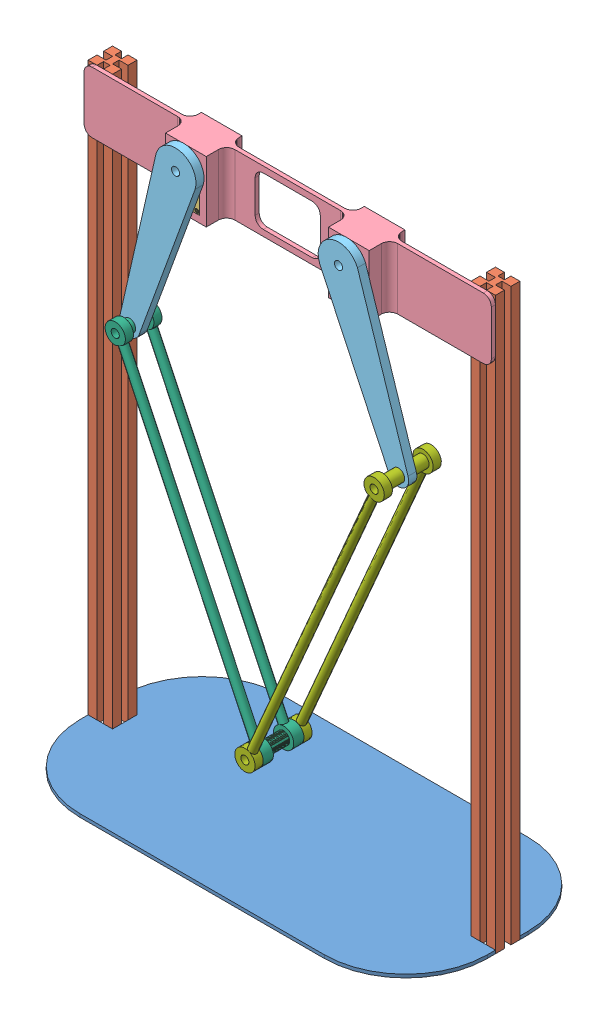
SolidWorks assembly 2dof, configuration Default. Lengths in mm.
Overall size (500 710.46 250).
10 component instances, 7 part files, 24 mates.
Components (placement in the parent):
- base_plate-1: base_plate [Default] at (211.4596 209.3847 404.3525) size (500 4 250)
- strud50-1: strud50 [Default] at (-27.5404 209.3847 411.3525) size (30 700 30)
- strud50-2: strud50 [Default] at (442.4596 209.3847 411.3525) size (30 700 30)
- DynamyxelXM150-1: DynamyxelXM150 [Default] at (111.4889 871.8847 405.3525) x (0 -1 0) z (-1 0 0) size (58.5 49.15 33.5)
- stand-1: stand [Default] at (211.4596 871.8847 419.3525) size (500 75 44)
- DynamyxelXM150-3: DynamyxelXM150 [Default] at (311.4596 871.8864 405.3525) x (0 -1 0) z (-1 0 0) size (58.5 49.15 33.5)
- up_link-1: up_link [Default] at (348.3193 794.4275 452.0025) x (0.929589 0.368597 0) z (0 0 1) size (50 237.5 10)
- up_link-2: up_link [Default] at (83.2023 791.4688 452.0025) x (0.959159 -0.282866 0) z (0 0 1) size (50 237.5 10)
- down_link2-1: down_link2 [Default] at (54.9157 695.5528 434.5025) x (0.903238 0.429141 0) z (0 0 1) size (25 425 50)
- down_link-2: down_link [Default] at (385.179 701.4686 422.0025) x (0.918027 -0.396518 0) z (0 0 1) size (25 425 70)
Mates (geometry in assembly coordinates):
- Coincident2: coincident aligned: plane of base_plate-1 through (-38.5404 213.3847 529.3525) normal (-1 0 0); plane of strud50-1 through (-38.5404 909.3847 411.3525) normal (-1 0 0)
- Coincident4: coincident aligned: plane of base_plate-1 through (461.4596 213.3847 529.3525) normal (1 0 0); plane of strud50-2 through (461.4596 909.3847 411.3525) normal (1 0 0)
- Coincident5: coincident anti-aligned: plane of strud50-1 through (-27.5404 909.3847 419.3525) normal (0 0 1); plane of stand-1 through (211.4596 871.8847 419.3525) normal (0 0 -1)
- Coincident6: coincident aligned: plane of strud50-1 through (-38.5404 909.3847 411.3525) normal (-1 0 0); plane of stand-1 through (-38.5404 834.3847 424.3525) normal (-1 0 0)
- Coincident7: coincident aligned: plane of strud50-2 through (442.4596 909.3847 411.3525) normal (0 1 0); plane of stand-1 through (-38.5404 909.3847 424.3525) normal (0 1 0)
- Coincident8: coincident anti-aligned: plane of DynamyxelXM150-1 through (94.7389 900.1347 449.3525) normal (-1 0 0); plane of stand-1 through (94.7389 842.6347 419.3525) normal (1 0 0)
- Coincident10: coincident anti-aligned: plane of stand-1 through (294.7096 842.633 419.3525) normal (1 0 0); plane of DynamyxelXM150-3 through (294.7096 900.1364 449.3525) normal (-1 0 0)
- Coincident11: coincident anti-aligned: plane of stand-1 through (294.7096 901.1364 419.3525) normal (0 -1 0); plane of DynamyxelXM150-3 through (327.2096 901.1364 449.3525) normal (0 1 0)
- Coincident14: coincident aligned: plane of DynamyxelXM150-1 through (111.4889 871.8847 449.3525) normal (0 0 1); plane of stand-1 through (211.4596 871.8847 449.3525) normal (0 0 1)
- Coincident15: coincident aligned: plane of stand-1 through (211.4596 871.8847 449.3525) normal (0 0 1); plane of DynamyxelXM150-3 through (311.4596 871.8864 449.3525) normal (0 0 1)
- Concentric1: concentric anti-aligned: cylinder of DynamyxelXM150-3 through (311.4596 887.3864 454.5025) axis (0 0 -1) radius 5; cylinder of up_link-1 through (311.4596 887.3864 415.233) axis (0 0 1) radius 5
- Coincident16: coincident anti-aligned: plane of DynamyxelXM150-3 through (311.4596 887.3864 452.0025) normal (0 0 1); plane of up_link-1 through (348.3193 794.4275 452.0025) normal (0 0 -1)
- Concentric2: concentric anti-aligned: cylinder of DynamyxelXM150-1 through (111.4889 887.3847 454.5025) axis (0 0 -1) radius 5; cylinder of up_link-2 through (111.4889 887.3847 415.233) axis (0 0 1) radius 5
- Coincident17: coincident anti-aligned: plane of DynamyxelXM150-1 through (111.4889 887.3847 452.0025) normal (0 0 1); plane of up_link-2 through (83.2023 791.4688 452.0025) normal (0 0 -1)
- Concentric3: concentric aligned: cylinder of up_link-2 through (54.9157 695.5528 462.0025) axis (0 0 -1) radius 7.5; cylinder of down_link2-1 through (54.9157 695.5528 469.5025) axis (0 0 -1) radius 7.5
- Width5: width anti-aligned: plane of down_link2-1 through (54.9157 695.5528 469.5025) normal (0 0 -1); plane of up_link-2 through (54.9157 695.5528 444.5025) normal (0 0 1); plane of down_link2-1 through (83.2023 791.4688 462.0025) normal (0 0 1); plane of up_link-2 through (83.2023 791.4688 452.0025) normal (0 0 -1)
- Concentric4: concentric aligned: cylinder of up_link-1 through (385.179 701.4686 462.0025) axis (0 0 -1) radius 7.5; cylinder of down_link-2 through (385.179 701.4686 482.0025) axis (0 0 -1) radius 7.5
- Width6: width anti-aligned: plane of down_link-2 through (385.179 701.4686 492.0025) normal (0 0 1); plane of up_link-1 through (385.179 701.4686 422.0025) normal (0 0 -1); plane of down_link-2 through (348.3193 794.4275 452.0025) normal (0 0 -1); plane of up_link-1 through (348.3193 794.4275 462.0025) normal (0 0 1)
- Concentric5: concentric aligned: cylinder of down_link2-1 through (226.5719 334.2577 469.5025) axis (0 0 -1) radius 7.5; cylinder of down_link-2 through (226.5719 334.2577 482.0025) axis (0 0 -1) radius 7.5
- Coincident18: coincident anti-aligned: plane of base_plate-1 through (-38.5404 219.3847 419.3525) normal (0 0 -1); plane of strud50-1 through (-27.5404 909.3847 419.3525) normal (0 0 1)
- Coincident20: coincident aligned: plane of base_plate-1 through (211.4596 209.3847 404.3525) normal (0 -1 0); plane of strud50-1 through (-27.5404 209.3847 411.3525) normal (0 -1 0)
- Coincident21: coincident anti-aligned: plane of base_plate-1 through (461.4596 219.3847 419.3525) normal (0 0 -1); plane of strud50-2 through (442.4596 909.3847 419.3525) normal (0 0 1)
- Coincident22: coincident aligned: plane of base_plate-1 through (211.4596 209.3847 404.3525) normal (0 -1 0); plane of strud50-2 through (442.4596 209.3847 411.3525) normal (0 -1 0)
- Coincident23: coincident anti-aligned: plane of DynamyxelXM150-1 through (127.2389 901.1347 449.3525) normal (0 1 0); plane of stand-1 through (94.7389 901.1347 419.3525) normal (0 -1 0)
